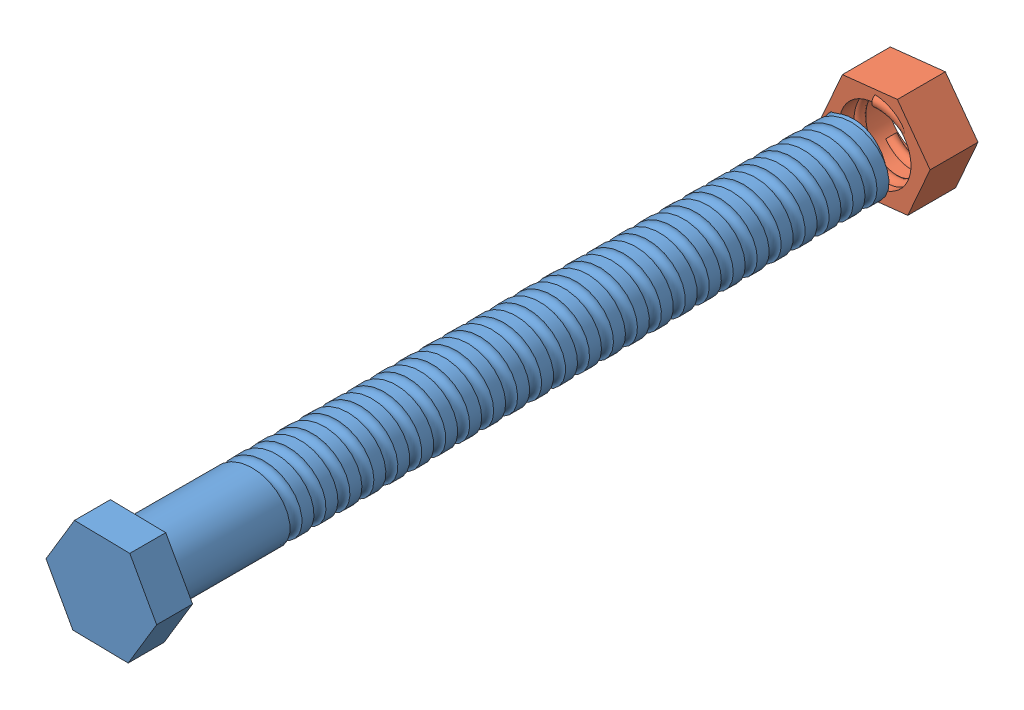
SolidWorks assembly Assemblage3, configuration Défaut. Lengths in mm.
Overall size (46.18 42.26 342.96).
2 component instances, 2 part files, 4 mates.
Components (placement in the parent):
- Pièce4-1: Pièce4 [Défaut] at (4.5655 -9.3339 467.3424) size (46.18 40.38 321.56)
- Pièce8-2: Pièce8 [Défaut] at (4.5655 -9.3339 139.3817) size (45.92 42.26 21.4)
Mates (geometry in assembly coordinates):
- Tangent10: tangent: cylinder of Pièce4-1 through (4.5655 -9.3339 167.3424) axis (0 0 1) radius 15; face of Pièce8-2
- Coaxiale4: concentric: cylinder of Pièce4-1 through (4.5655 -9.3339 167.3424) axis (0 0 1) radius 15; cylinder of Pièce8-2 through (4.5655 -9.3339 139.3817) axis (0 0 1) radius 15
- Coaxiale5: concentric: cylinder of Pièce4-1 through (4.5655 -9.3339 167.3424) axis (0 0 1) radius 15; cylinder of Pièce8-2 through (4.5655 -9.3339 139.3817) axis (0 0 1) radius 15
- Hélicoïdale1: screw = 1: cylinder of Pièce4-1 through (4.5655 -9.3339 167.3424) axis (0 0 1) radius 15; cylinder of Pièce8-2 through (4.5655 -9.3339 139.3817) axis (0 0 1) radius 15
